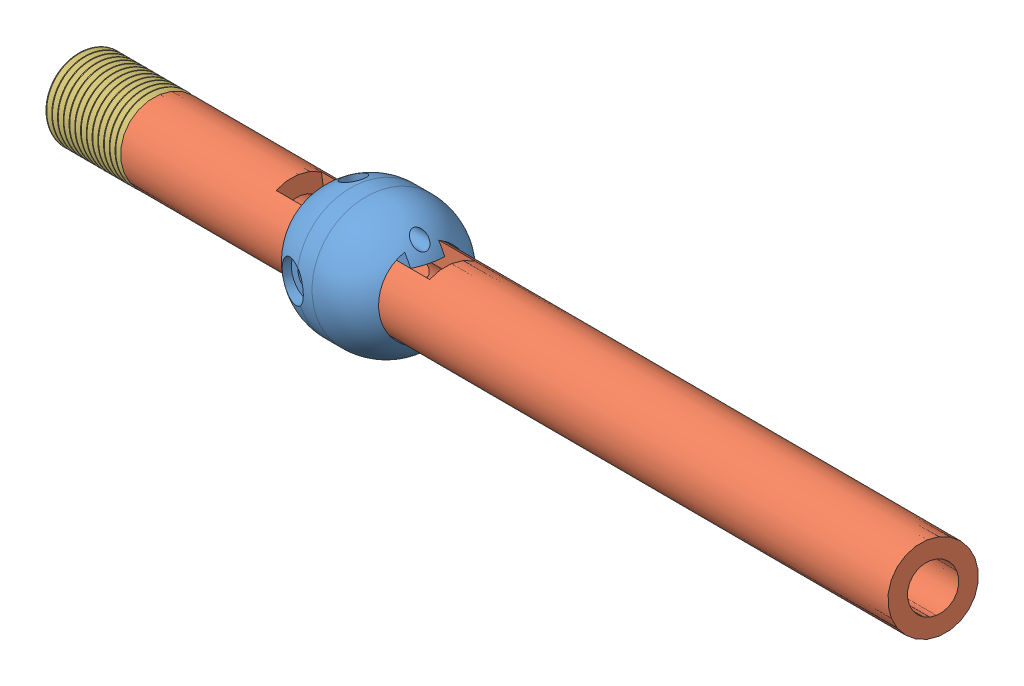
SolidWorks assembly slider assembly v-3 06-Nov-2017, configuration Default. Lengths in mm.
Overall size (111.34 32.4 32.77).
4 component instances, 3 part files, 1 mates.
Components (placement in the parent):
- slider v-5 06-Nov-2017-1: slider v-5 06-Nov-2017 [Default] at (18.8935 64.387 89.0476) x (-0.188728 0.042691 0.981101) z (-0.967993 -0.176396 -0.17853) size (13 16.42 14.41)
- slider handle assembly v-4 06-Nov-2017-1: slider handle assembly v-4 06-Nov-2017 [Default] at (25.2345 14.1232 10.7958) x (0.967993 0.176396 0.17853) z (-0.179481 -0.010686 0.983703) size (110.35 13 13)
  - wheel_handle_body_slider v-4 06-Nov-2017-1: wheel_handle_body_slider v-4 06-Nov-2017 [Default] at (-10.0168 48.9172 77.5775) size (100 7.94 7.94)
  - M8X0.75-1: M8X0.75 [91290A414] at (-10.0168 48.9172 77.5775) x (0 0 -1) z (1 0 0) size (13 13 10.51)
Mates (geometry in assembly coordinates):
- Concentric2: concentric anti-aligned: circle of slider v-5 06-Nov-2017-1; circle of slider handle assembly v-4 06-Nov-2017-1/M8X0.75-1
